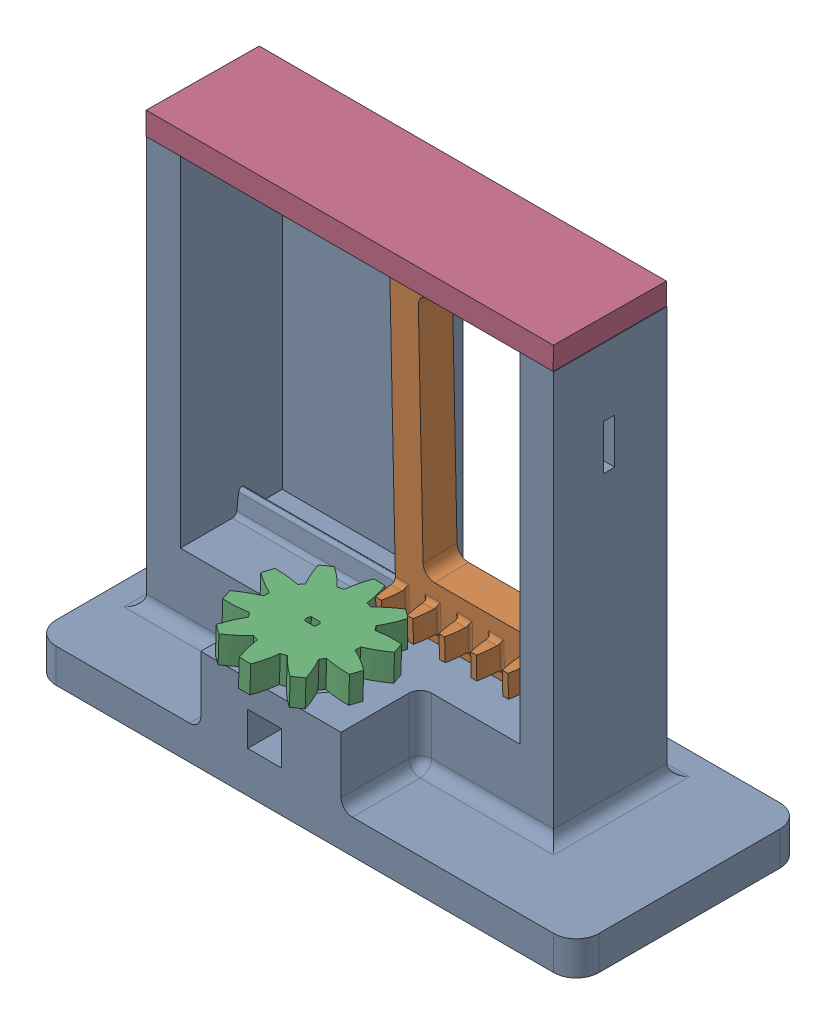
SolidWorks assembly Final_Assembly_Of_Rain_Bot, configuration Default. Lengths in mm.
Overall size (240 205 107.87).
4 component instances, 4 part files, 3 mates.
Components (placement in the parent):
- Rain_Bot_Frame-1: Rain_Bot_Frame [Default] at (609.64 808.8536 1262.8157) size (240 195 100)
- Door_with_Gear_Assembly-1: Door_with_Gear_Assembly [Default] at (632.309 863.6158 1257.8472) x (-1 0 0) z (0 0.020948 -0.999781) size (75.03 150 25)
- Geared_Pulley-1: Geared_Pulley [Default] at (590.1123 855.4597 1290.4094) x (0.999633 -0.025393 -0.009451) z (0.009579 0.004919 0.999942) size (58.61 12 60)
- Rain_Bot_Lid-1: Rain_Bot_Lid [Default] at (557.0137 1013.6163 1251.8118) x (1 0 0) z (0 -0.009142 -0.999958) size (180 20 50)
Mates (geometry in assembly coordinates):
- Coincident7: coincident anti-aligned: line of Door_with_Gear_Assembly-1 through (669.809 1003.6636 1257.0308) axis (-1 0 0); line of Rain_Bot_Lid-1 through (517.8891 1003.6636 1257.0308) axis (1 0 0)
- Coincident8: coincident aligned: line of Rain_Bot_Frame-1 through (519.64 853.8536 1246.3902) axis (1 0 0); line of Door_with_Gear_Assembly-1 through (594.809 853.8536 1246.3902) axis (1 0 0)
- Coincident10: coincident anti-aligned: line of Rain_Bot_Frame-1 through (669.64 1003.8536 1277.8157) axis (1 0 0); line of Rain_Bot_Lid-1 through (684.3891 1003.8536 1277.8157) axis (-1 0 0)
